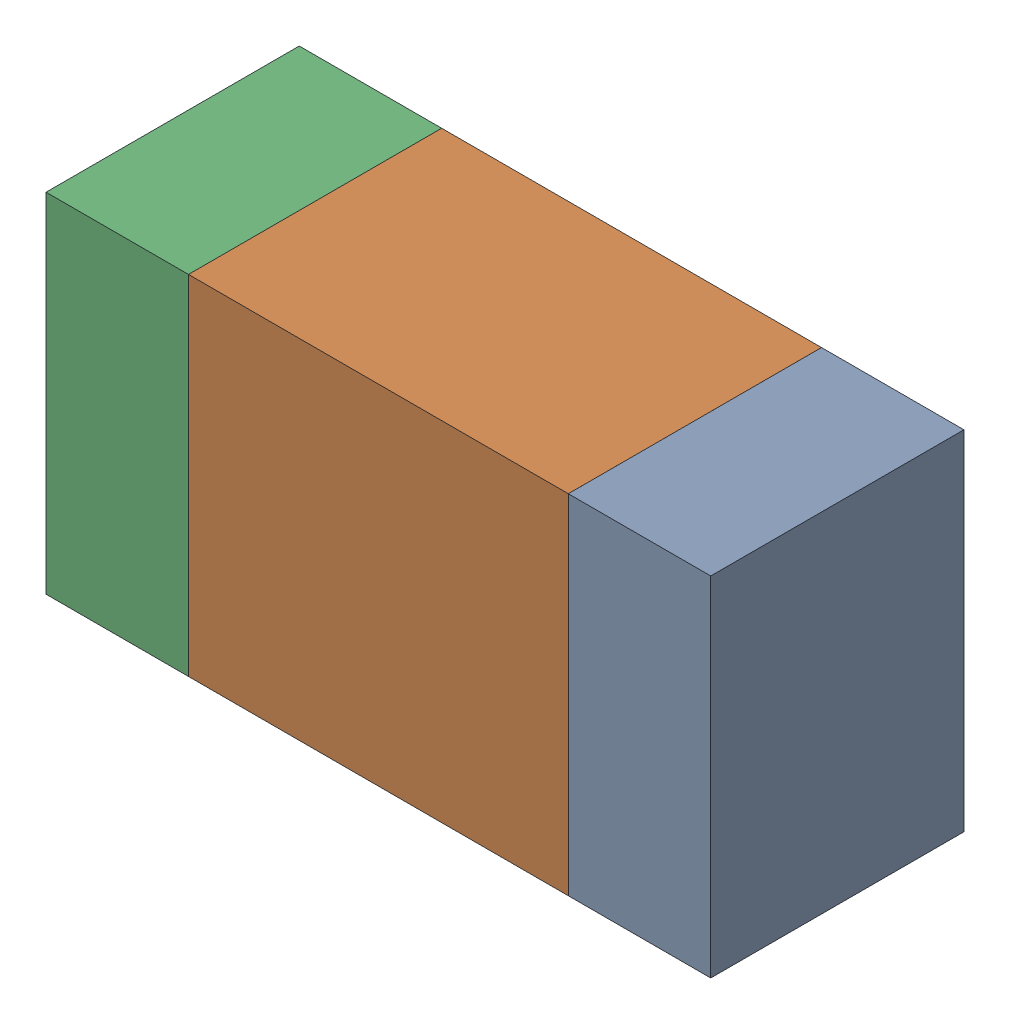
SolidWorks assembly R315_2PCB, configuration Default. Lengths in mm.
Overall size (1.05 0.55 0.4).
6 component instances, 2 part files, 0 mates.
Components (placement in the parent):
- 854785432-1: 854785432 [Default] at (135.1126 95.1999 -2.0638) size (0.22 0.55 0.4)
  - Extruded-1: Extruded [Default] at origin size (0.22 0.55 0.4)
- 854785568-1: 854785568 [Default] at (134.7001 95.1999 -2.0638) size (0.6 0.55 0.4)
  - Extruded_2-1: Extruded_2 [Default] at origin size (0.6 0.55 0.4)
- 854785432-2: 854785432 [Default] at (134.2876 95.1999 -2.0638) size (0.22 0.55 0.4)
  - Extruded-1: Extruded [Default] at origin size (0.22 0.55 0.4)
